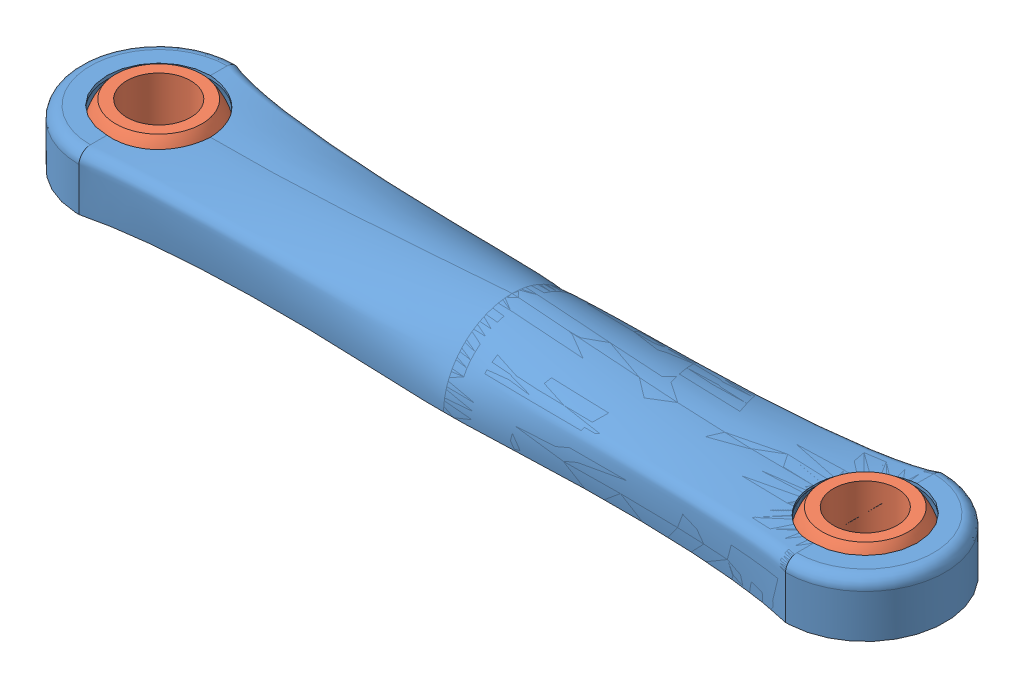
SolidWorks assembly ball_linkage_new, configuration Default. Lengths in mm.
Overall size (38 13.16 13.16).
3 component instances, 2 part files, 3 mates.
Components (placement in the parent):
- SD-205 Steering Linkage_new-1: SD-205 Steering Linkage_new [Default] at (9.4859 26.1187 40.302) size (38 13.16 13.16)
- ball linkage ball 4 40-1: ball linkage ball 4 40 [Default] at (-6.0141 27.3187 40.302) size (4.75 2.88 4.75)
- ball linkage ball 4 40-2: ball linkage ball 4 40 [Default] at (24.9859 27.3187 40.302) size (4.75 2.88 4.75)
Mates (geometry in assembly coordinates):
- Concentric1: concentric: sphere of SD-205 Steering Linkage_new-1; sphere of ball linkage ball 4 40-1
- Concentric2: concentric: circle of SD-205 Steering Linkage_new-1; cylinder of ball linkage ball 4 40-1 through (-6.0141 -422.3252 40.302) axis (0 -1 0) radius 1.4
- Concentric3: concentric: sphere of SD-205 Steering Linkage_new-1; sphere of ball linkage ball 4 40-2
